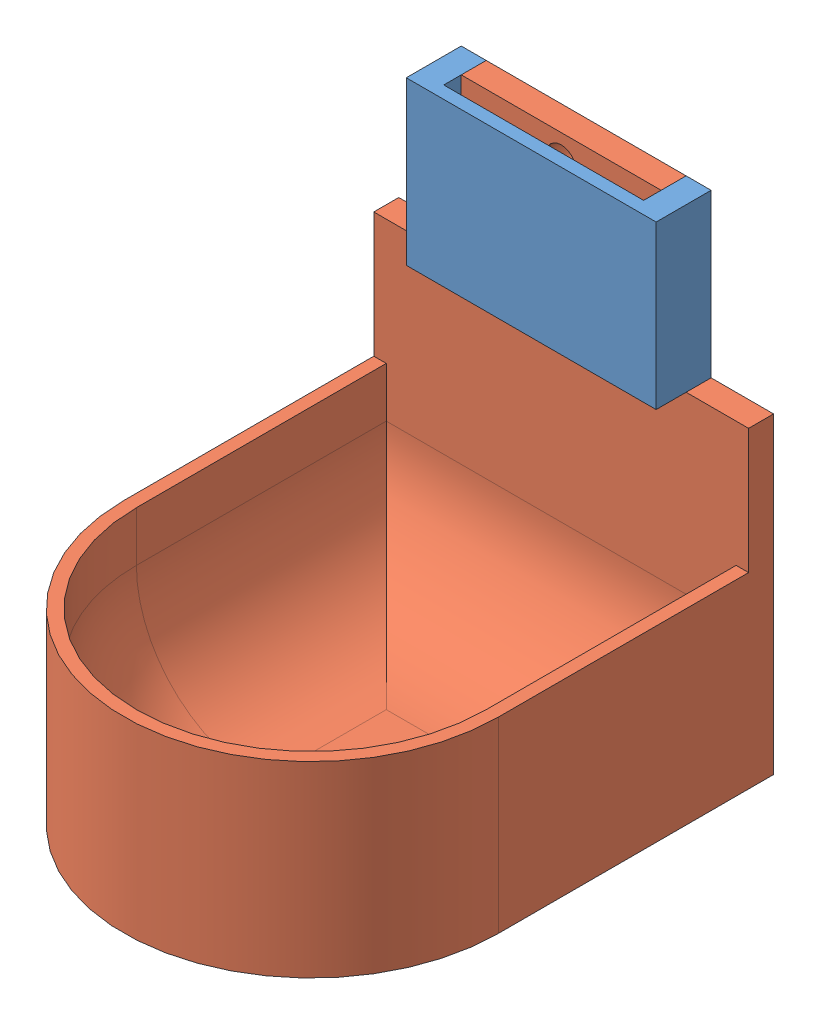
SolidWorks assembly coin-dish, configuration Default. Lengths in mm.
Overall size (38.1 48.26 46.99).
2 component instances, 2 part files, 3 mates.
Components (placement in the parent):
- coin-dish-chute-1: coin-dish-chute [Default] at (22.3858 18.2647 37.6412) x (-1 0 0) z (0 0 -1) size (25.4 16.51 5.59)
- coin-dish-combined-1: coin-dish-combined [Default] at (-9.3642 -13.4853 34.5932) size (38.1 48.26 46.99)
Mates (geometry in assembly coordinates):
- Coincident1: coincident anti-aligned: plane of coin-dish-chute-1 through (19.8458 34.7747 32.0532) normal (-1 0 0); plane of coin-dish-combined-1 through (19.8458 18.2647 34.5932) normal (1 0 0)
- Coincident2: coincident aligned: plane of coin-dish-chute-1 through (22.3858 18.2647 32.0532) normal (0 0 -1); plane of coin-dish-combined-1 through (-9.3642 -13.4853 32.0532) normal (0 0 -1)
- Coincident3: coincident aligned: plane of coin-dish-chute-1 through (22.3858 34.7747 36.3712) normal (0 1 0); plane of coin-dish-combined-1 through (19.8458 34.7747 34.5932) normal (0 1 0)
